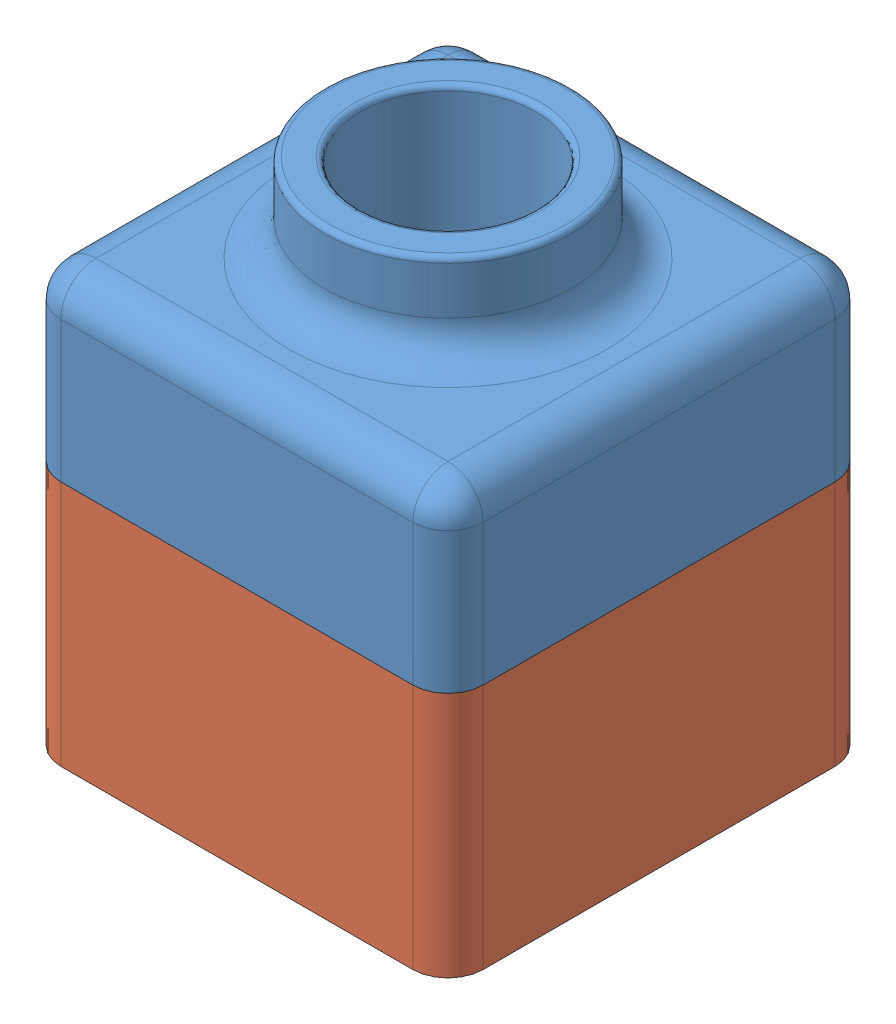
SolidWorks assembly leccion2ensamblaje, configuration Default. Lengths in mm.
Overall size (120 145 120).
2 component instances, 2 part files, 3 mates.
Components (placement in the parent):
- leccion1avilasanchez-3: leccion1avilasanchez [Default] at (-38.7287 37.2053 153.4515) size (120 75 120)
- leccion2avilasanchez-3: leccion2avilasanchez [Default] at (-38.7287 -32.7947 33.4515) x (1 0 0) z (0 1 0) size (120 120 90)
Mates (geometry in assembly coordinates):
- Coincident7: coincident: line of leccion1avilasanchez-3 through (-28.7287 37.2053 33.4515) axis (1 0 0); line of leccion2avilasanchez-3 through (71.2713 37.2053 33.4515) axis (-1 0 0)
- Coincident10: coincident: line of leccion1avilasanchez-3 through (-28.7287 37.2053 153.4515) axis (1 0 0); line of leccion2avilasanchez-3 through (-28.7287 37.2053 153.4515) axis (1 0 0)
- Coincident11: coincident aligned: plane of leccion1avilasanchez-3 through (81.2713 87.2053 153.4515) normal (1 0 0); plane of leccion2avilasanchez-3 through (81.2713 57.2053 33.4515) normal (1 0 0)
